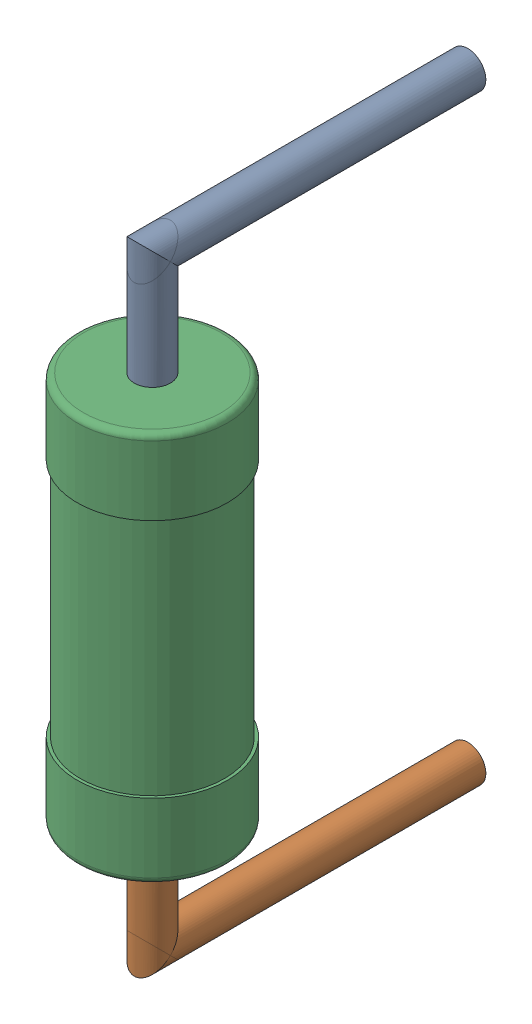
SolidWorks assembly RE.step, configuration Default. Lengths in mm.
Overall size (2.5 10.6 6.5).
3 component instances, 3 part files, 0 mates.
Components (placement in the parent):
- Res_Vishay_BC_Components_MRS25000C1101FCT00_eec.step-1: Res_Vishay_BC_Components_MRS25000C1101FCT00_eec.step [Default] at (30.607 20.955 0) x (0 -1 0) z (0 0 1) size (2.05 0.6 5.55)
- Res_Vishay_BC_Components_MRS25000C1101FCT00_eec-2.step-1: Res_Vishay_BC_Components_MRS25000C1101FCT00_eec-2.step [Default] at (30.607 20.955 0) x (0 -1 0) z (0 0 1) size (2.05 0.6 5.55)
- Res_Vishay_BC_Components_MRS25000C1101FCT00_eec-3.step-1: Res_Vishay_BC_Components_MRS25000C1101FCT00_eec-3.step [Default] at (30.607 20.955 0) x (0 -1 0) z (0 0 1) size (6.5 2.5 2.5)
